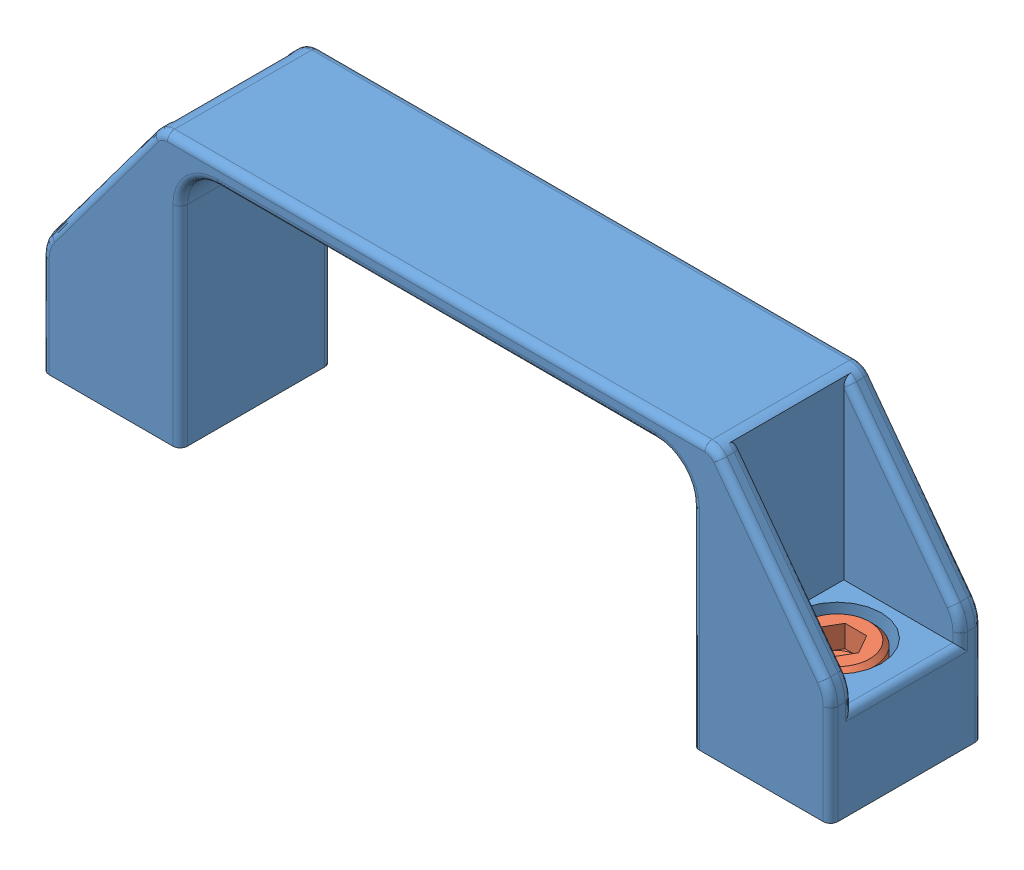
SolidWorks assembly handle, configuration Default. Lengths in mm.
Overall size (107.35 42.5 20.65).
3 component instances, 2 part files, 4 mates.
Components (placement in the parent):
- handle-1: handle [Default] at origin size (107.35 36.5 20.65)
- socket head cap screw_am-1: socket head cap screw_am [B18.3.1M - 6 x 1.0 x 12 Hex SHCS -- 12NHX] at (44.25 12 0) x (0 -1 0) z (0 0 1) size (18 10 10)
- socket head cap screw_am-2: socket head cap screw_am [B18.3.1M - 6 x 1.0 x 12 Hex SHCS -- 12NHX] at (-44.25 12 0) x (0 -1 0) z (0 0 1) size (18 10 10)
Mates (geometry in assembly coordinates):
- Concentric1: concentric anti-aligned: cylinder of handle-1 through (44.25 33.5 0) axis (0 -1 0) radius 3.25; cylinder of socket head cap screw_am-1 through (44.25 43.75 0) axis (0 1 0) radius 5
- Coincident1: coincident anti-aligned: plane of handle-1 through (0 6 0) normal (0 1 0); plane of socket head cap screw_am-1 through (49.25 6 0) normal (0 -1 0)
- Concentric2: concentric anti-aligned: cylinder of handle-1 through (-44.25 33.5 0) axis (0 -1 0) radius 3.25; cylinder of socket head cap screw_am-2 through (-44.25 43.75 0) axis (0 1 0) radius 5
- Coincident2: coincident anti-aligned: plane of handle-1 through (0 6 0) normal (0 1 0); plane of socket head cap screw_am-2 through (-39.25 6 0) normal (0 -1 0)
